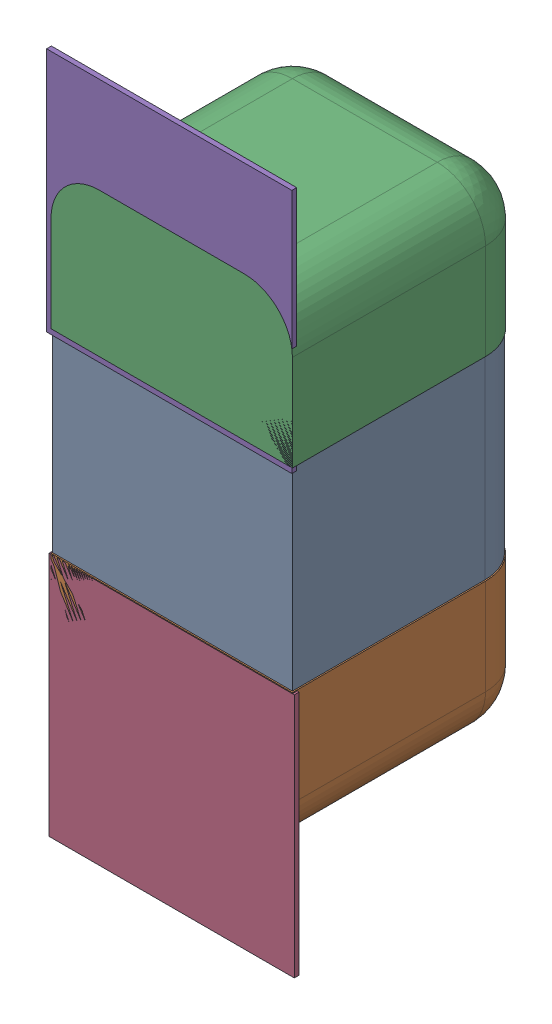
SolidWorks assembly C68, configuration Défaut. Lengths in mm.
Overall size (0.51 1.41 0.5).
8 component instances, 4 part files, 0 mates.
Components (placement in the parent):
- 6501210464-1: 6501210464 [Défaut] at (19.3802 -8.9536 -2.0818) x (0 1 0) z (-1 0 0) size (1 0.5 0.5)
  - Open CASCADE STEP translator 7.5 2.33.1.1-1: Open CASCADE STEP translator 7.5 2.33.1.1 [Défaut] at origin size (0.4 0.5 0.5)
  - Open CASCADE STEP translator 7.5 2.33.1.2-1: Open CASCADE STEP translator 7.5 2.33.1.2 [Défaut] at origin size (0.3 0.5 0.5)
  - Open CASCADE STEP translator 7.5 2.33.1.3-1: Open CASCADE STEP translator 7.5 2.33.1.3 [Défaut] at origin size (0.3 0.5 0.5)
- 6504207776-1: 6504207776 [Défaut] at (19.3802 -9.4109 -2.0918) size (0.51 0.51 0.01)
  - Extruded-1: Extruded [Défaut] at origin size (0.51 0.51 0.01)
- 6504207776-2: 6504207776 [Défaut] at (19.375 -8.5086 -2.0918) size (0.51 0.51 0.01)
  - Extruded-1: Extruded [Défaut] at origin size (0.51 0.51 0.01)
